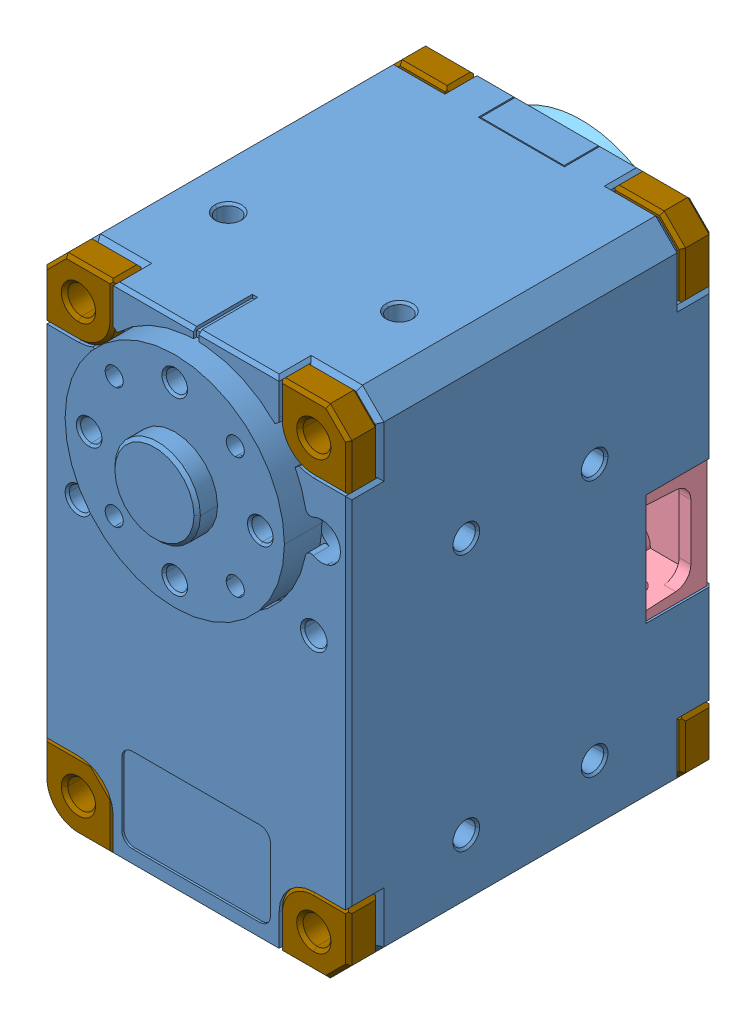
SolidWorks assembly ARMUS-100-005, configuration Défaut. Lengths in mm.
Overall size (28.5 46.5 40.9).
25 component instances, 9 part files, 0 mates.
Components (placement in the parent):
- ARMUS-100-005.stp-1: ARMUS-100-005.stp [Défaut] at origin size (28.5 46.5 40.9)
  - DC11_A01_DUMMY.stp-1: DC11_A01_DUMMY.stp [Défaut] at origin size (28.5 46.5 37.9)
  - DX124_SCREW-COVER.stp-1: DX124_SCREW-COVER.stp [Défaut] at (11.75 0 13.7) x (-1 0 0) z (0 1 0) size (3.5 30.65 3.5)
  - B3B-EH.stp-1: B3B-EH.stp [Défaut] at (10.15 -14.1 -3.8) x (0 -1 0) z (1 0 0) size (10 9.2 3.8)
  - B3B-EH.stp-2: B3B-EH.stp [Défaut] at (-10.15 -14.1 -3.8) x (0 1 0) z (-1 0 0) size (10 9.2 3.8)
  - DC11_A01_CASE_CVR_DUMMY.stp-1: DC11_A01_CASE_CVR_DUMMY.stp [Défaut] at origin size (28.3 17.62 8.31)
  - DC11_A01_IDLER_DUMMY.stp-1: DC11_A01_IDLER_DUMMY.stp [Défaut] at (0 0 -19) x (1 0 0) z (0 1 0) size (20.5 3.5 20.5)
  - DC11_A01_IDLER_CAP_DUMMY.stp-1: DC11_A01_IDLER_CAP_DUMMY.stp [Défaut] at (0 0 -18.8) x (1 0 0) z (0 -1 0) size (10.1 5.2 10.37)
  - DC11_A01_IDLER_SCREW.stp-1: DC11_A01_IDLER_SCREW.stp [Défaut] at (0 0 -15.1) x (-1 0 0) z (0 -1 0) size (5 5.01 5)
  - FHS_M2_5X10.stp-1: FHS_M2_5X10.stp [Défaut] at (11 8 12.95) x (-1 0 0) z (0 1 0) size (5 10.01 5)
  - FHS_M2_5X10.stp-2: FHS_M2_5X10.stp [Défaut] at (-11 8 12.95) x (-1 0 0) z (0 1 0) size (5 10.01 5)
  - FHS_M2_5X10.stp-3: FHS_M2_5X10.stp [Défaut] at (-11 -32 12.95) x (-1 0 0) z (0 1 0) size (5 10.01 5)
  - FHS_M2_5X10.stp-4: FHS_M2_5X10.stp [Défaut] at (11 -32 12.95) x (-1 0 0) z (0 1 0) size (5 10.01 5)
  - FHS_M2_5X10.stp-5: FHS_M2_5X10.stp [Défaut] at (-11 8 -12.95) x (1 0 0) z (0 1 0) size (5 10.01 5)
  - FHS_M2_5X10.stp-6: FHS_M2_5X10.stp [Défaut] at (11 8 -12.95) x (1 0 0) z (0 1 0) size (5 10.01 5)
  - FHS_M2_5X10.stp-7: FHS_M2_5X10.stp [Défaut] at (-11 -32 -12.95) x (1 0 0) z (0 1 0) size (5 10.01 5)
  - FHS_M2_5X10.stp-8: FHS_M2_5X10.stp [Défaut] at (11 -32 -12.95) x (1 0 0) z (0 1 0) size (5 10.01 5)
  - DC11_A01_SPACER_DUMMY.stp-1: DC11_A01_SPACER_DUMMY.stp [Défaut] at (11 8 14.2) x (-1 0 0) z (0 0 1) size (6.5 6.5 3.9)
  - DC11_A01_SPACER_DUMMY.stp-2: DC11_A01_SPACER_DUMMY.stp [Défaut] at (-11 8 14.2) x (0 -1 0) z (0 0 1) size (6.5 6.5 3.9)
  - DC11_A01_SPACER_DUMMY.stp-3: DC11_A01_SPACER_DUMMY.stp [Défaut] at (-11 -32 14.2) x (-1 0 0) z (0 0 1) size (6.5 6.5 3.9)
  - DC11_A01_SPACER_DUMMY.stp-4: DC11_A01_SPACER_DUMMY.stp [Défaut] at (11 -32 14.2) x (0 1 0) z (0 0 1) size (6.5 6.5 3.9)
  - DC11_A01_SPACER_DUMMY.stp-5: DC11_A01_SPACER_DUMMY.stp [Défaut] at (11 8 -14.2) x (0 -1 0) z (0 0 -1) size (6.5 6.5 3.9)
  - DC11_A01_SPACER_DUMMY.stp-6: DC11_A01_SPACER_DUMMY.stp [Défaut] at (-11 8 -14.2) x (1 0 0) z (0 0 -1) size (6.5 6.5 3.9)
  - DC11_A01_SPACER_DUMMY.stp-7: DC11_A01_SPACER_DUMMY.stp [Défaut] at (11 -32 -14.2) x (-1 0 0) z (0 0 -1) size (6.5 6.5 3.9)
  - DC11_A01_SPACER_DUMMY.stp-8: DC11_A01_SPACER_DUMMY.stp [Défaut] at (-11 -32 -14.2) x (0 1 0) z (0 0 -1) size (6.5 6.5 3.9)
